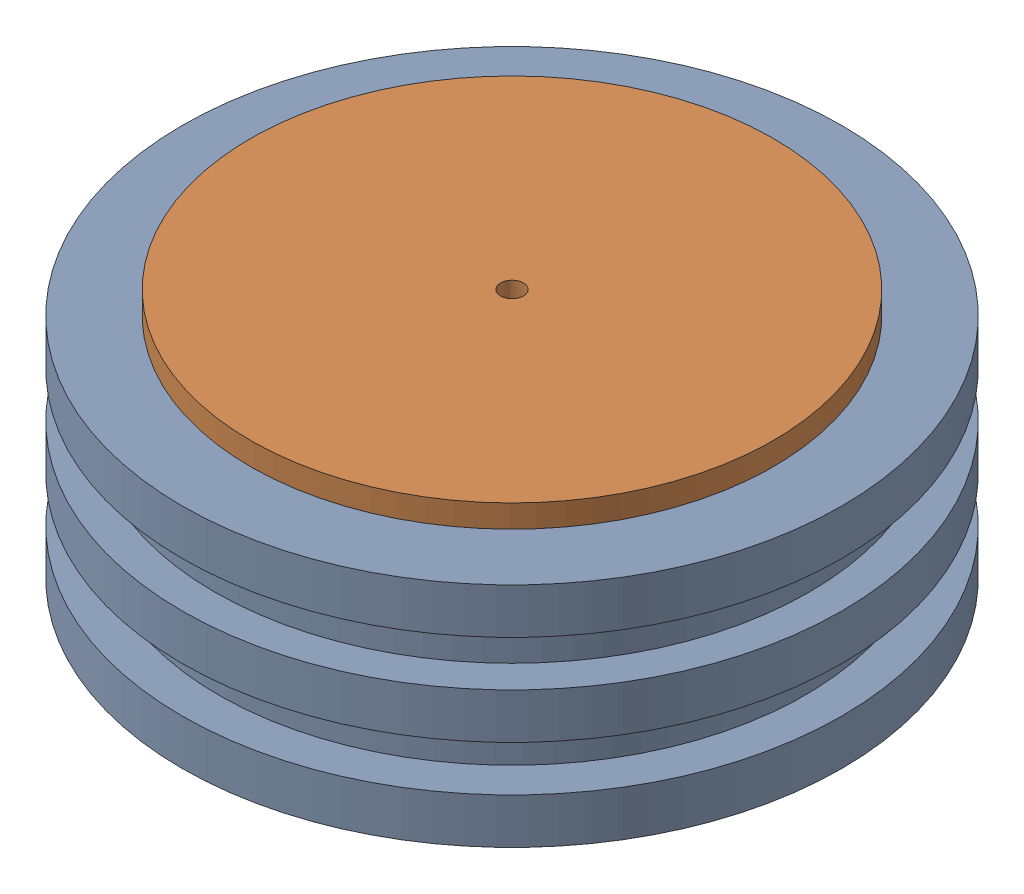
SolidWorks assembly Plunger_Assembly1, configuration Default. Lengths in mm.
Overall size (159.38 55 159.38).
2 component instances, 2 part files, 2 mates.
Components (placement in the parent):
- Unattached_plunger_bottom-1: Unattached_plunger_bottom [Default] at (35.7075 21.2266 77.4939) size (145 50 145)
- Unattached_plunger_top-1: Unattached_plunger_top [Default] at (35.7075 35.6147 77.4939) x (0.833673 0 -0.552259) z (0.552259 0 0.833673) size (115 30.61 115)
Mates (geometry in assembly coordinates):
- Concentric2: concentric anti-aligned: cylinder of Unattached_plunger_bottom-1 through (35.7075 41.2266 77.4939) axis (0 1 0) radius 47.5; cylinder of Unattached_plunger_top-1 through (35.7075 76.2266 77.4939) axis (0 -1 0) radius 47.5
- Coincident1: coincident anti-aligned: plane of Unattached_plunger_bottom-1 through (35.7075 71.2266 77.4939) normal (0 1 0); plane of Unattached_plunger_top-1 through (35.7075 71.2266 77.4939) normal (0 -1 0)
